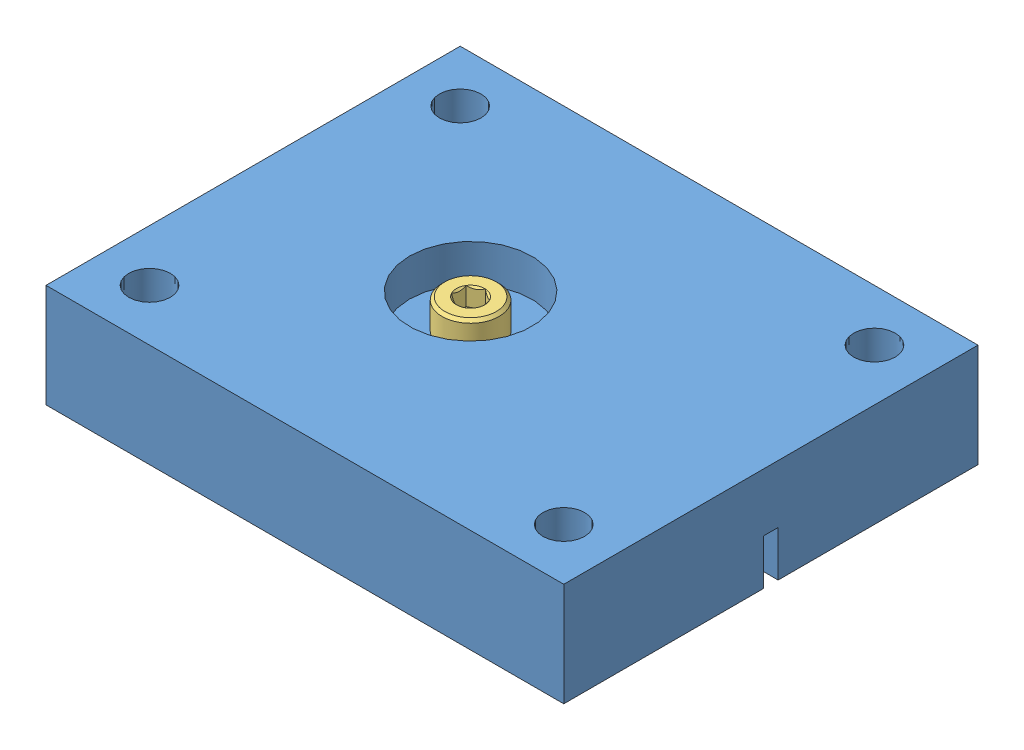
SolidWorks assembly MS-SA-0013g-03-Gripper Electromagnet Assembly, configuration Default. Lengths in mm.
Overall size (63.5 22.11 50.8).
3 component instances, 3 part files, 6 mates.
Components (placement in the parent):
- MS-P-0061-03-Electromagnet Bellypan Mount-2: MS-P-0061-03-Electromagnet Bellypan Mount [Default] at (22.7045 41.7802 51.2327) x (1 0 0) z (0 -1 0) size (63.5 50.8 12.7)
- MS-C-0033-Gripper Permanent Electromagnet-1: MS-C-0033-Gripper Permanent Electromagnet [Default] at (17.6245 19.6682 51.2327) x (0.56903 0 -0.822316) z (0.822316 0 0.56903) size (15 15 15)
- 91292A107_TYPE 18-8 SS SOCKET HEAD CAP SCREW-1: 91292A107_TYPE 18-8 SS SOCKET HEAD CAP SCREW [91292A107] at (17.6245 31.2082 51.2327) x (0.999102 0 0.042367) z (0 -1 0) size (7 7 10.79)
Mates (geometry in assembly coordinates):
- Concentric1: concentric: cylinder of MS-P-0061-03-Electromagnet Bellypan Mount-1 through (22.9801 17.2218 58.6937) axis (0 1 0) radius 7.493; cylinder of MS-C-0033-Gripper Permanent Electromagnet-1 through (17.6245 34.6682 51.2327) axis (0 -1 0) radius 7.5
- Coincident1: coincident anti-aligned: plane of MS-P-0061-03-Electromagnet Bellypan Mount-1 through (22.9801 17.2218 58.6937) normal (0 1 0); plane of MS-C-0033-Gripper Permanent Electromagnet-1 through (17.6245 19.6682 51.2327) normal (0 -1 0)
- Concentric4: concentric anti-aligned: circle of MS-C-0033-Gripper Permanent Electromagnet-1; circle of MS-P-0061-03-Electromagnet Bellypan Mount-2
- Coincident2: coincident anti-aligned: plane of MS-C-0033-Gripper Permanent Electromagnet-1 through (17.6245 34.6682 51.2327) normal (0 1 0); plane of MS-P-0061-03-Electromagnet Bellypan Mount-2 through (22.7045 34.6682 51.2327) normal (0 -1 0)
- Concentric5: concentric aligned: circle of MS-P-0061-03-Electromagnet Bellypan Mount-2; circle of 91292A107_TYPE 18-8 SS SOCKET HEAD CAP SCREW-1
- Coincident3: coincident anti-aligned: plane of MS-P-0061-03-Electromagnet Bellypan Mount-2 through (22.7045 37.2082 51.2327) normal (0 1 0); circle of 91292A107_TYPE 18-8 SS SOCKET HEAD CAP SCREW-1
